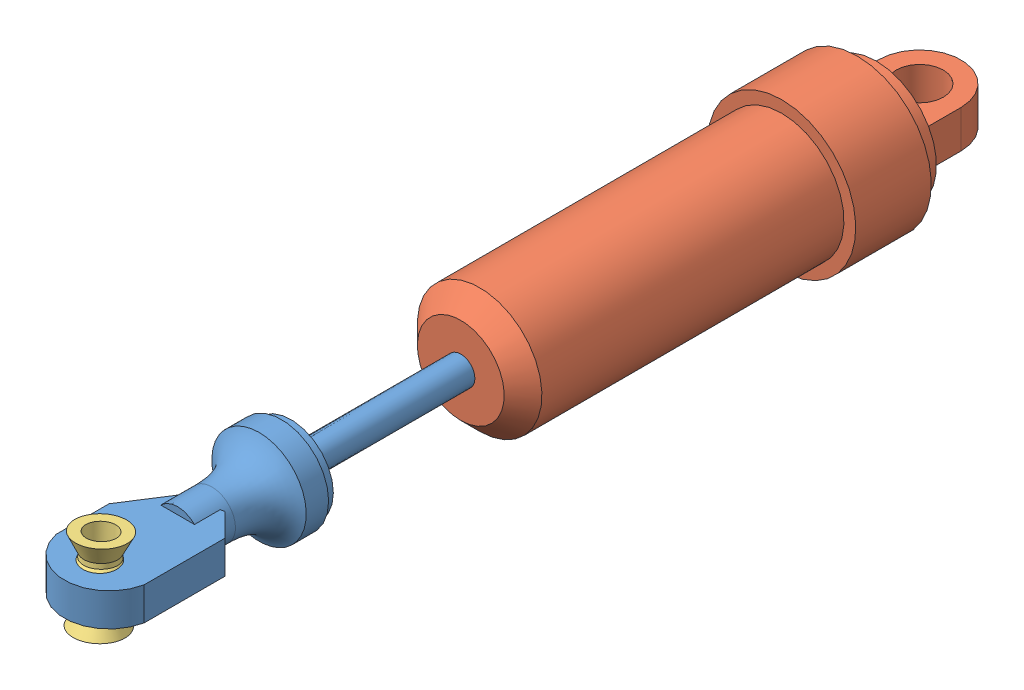
SolidWorks assembly Suspension_fore, configuration Default. Lengths in mm.
Overall size (15.7 15.7 95).
3 component instances, 3 part files, 4 mates.
Components (placement in the parent):
- Suspension Inner_fore-1: Suspension Inner_fore [Default] at (14.4288 30.3657 20.0829) size (10 10 58)
- Suspension Outer_fore-1: Suspension Outer_fore [Default] at (14.4288 30.3657 36.0829) x (0 -1 0) z (0 0 -1) size (15.7 15.7 53)
- Turnbuckle Ball Spacer-1: Turnbuckle Ball Spacer [Default] at (14.4288 30.3657 74.3221) x (-0.040986 0.99667 -0.07049) z (-0.169655 0.062583 0.983514) size (8.25 5.2 5.2)
Mates (geometry in assembly coordinates):
- Concentric1: concentric: sphere of Suspension Inner_fore-1; sphere of Turnbuckle Ball Spacer-1
- Concentric2: concentric: cylinder of Suspension Inner_fore-1 through (14.4288 30.3657 54.0829) axis (0 0 -1) radius 1.5; cylinder of Suspension Outer_fore-1 through (14.4288 30.3657 1.0829) axis (0 0 1) radius 1.5
- LimitDistance1: limit distance = 18 mm: plane of Suspension Outer_fore-1 through (14.4288 30.3657 36.0829) normal (0 0 1); plane of Suspension Inner_fore-1 through (14.4288 30.3657 54.0829) normal (0 0 -1)
- Parallel1: parallel: plane of Suspension Inner_fore-1 through (14.4288 28.6157 73.3329) normal (0 -1 0); plane of Suspension Outer_fore-1 through (14.4288 32.3657 -12.5421) normal (0 1 0)
